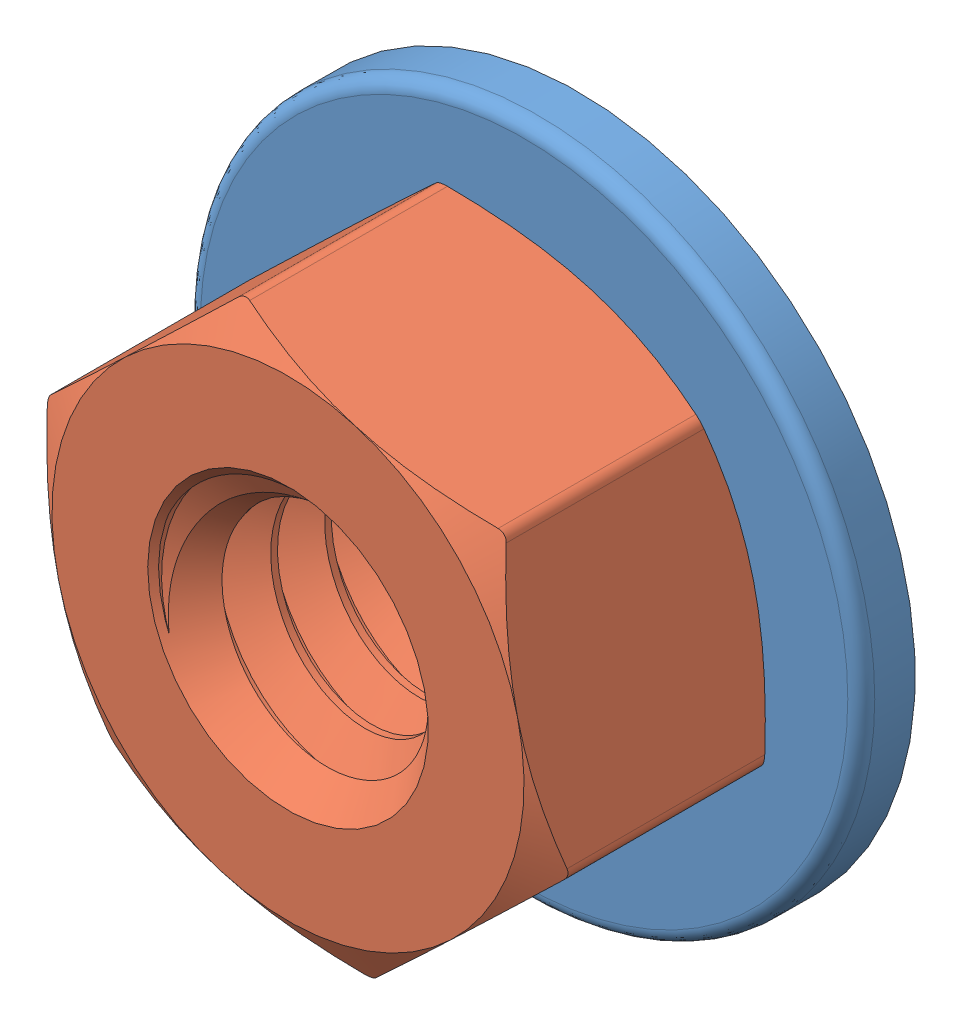
SolidWorks assembly 1_4_20_Nut Washer Assembly, configuration Default. Lengths in mm.
Overall size (15.88 15.88 7.21).
2 component instances, 2 part files, 2 mates.
Components (placement in the parent):
- 90107A029_316 Stainless Steel Washer-1: 90107A029_316 Stainless Steel Washer [90107A029] at (-22.8159 -23.9196 28.2903) size (15.88 15.88 1.27)
- 95462A029_Medium-Strength Steel Hex Nut-1: 95462A029_Medium-Strength Steel Hex Nut [95462A029] at (-22.8159 -23.9196 31.7034) x (0.972065 0.23471 0) z (0 0 1) size (11.11 12.75 6.32)
Mates (geometry in assembly coordinates):
- Concentric1: concentric aligned: circle of 90107A029_316 Stainless Steel Washer-1; circle of 95462A029_Medium-Strength Steel Hex Nut-1
- Coincident1: coincident anti-aligned: plane of 90107A029_316 Stainless Steel Washer-1 through (-22.8159 -23.9196 28.9253) normal (0 0 1); plane of 95462A029_Medium-Strength Steel Hex Nut-1 through (-22.8159 -23.9196 28.9253) normal (0 0 -1)
